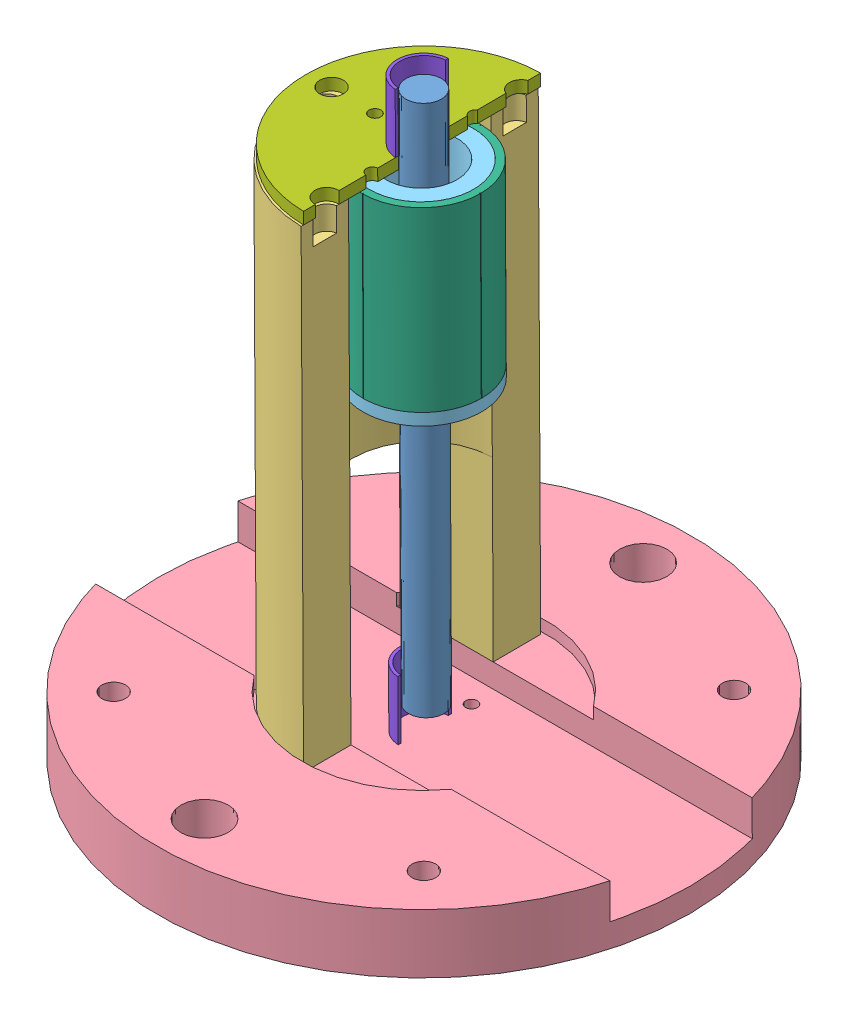
SolidWorks assembly FinalFinal10, configuration Default. Lengths in mm.
Overall size (48.22 72.45 49.76).
10 component instances, 8 part files, 10 mates.
Components (placement in the parent):
- RodCapacitance-1: RodCapacitance [Default] at (-34.9973 26.4173 110.2163) x (-0.024859 -0.005123 0.999678) z (-0.999691 0.000127 -0.024859) size (3 45 3)
- Bearing-7: Bearing [Default] at (-33.9141 58.2749 108.56) x (0 -0.999987 -0.005125) z (-0.999781 0.000107 -0.020933) size (1.6 1.6 1.6)
- Bearing-8: Bearing [Default] at (-37.2061 58.0134 109.9357) x (0 -0.999987 -0.005125) z (-0.999781 0.000107 -0.020933) size (1.6 1.6 1.6)
- 套筒-1: 套筒 [默认] at (-35 26.4344 110.4244) x (-1 0 0) z (0 0.005125 -0.999987) size (20 40 20)
- 底座1-1: 底座1 [默认] at (-35 27.4344 110.4295) x (0 0.005125 -0.999987) z (-1 0 0) size (45 5 45)
- MACOR-2: MACOR [Default] at (-34.9374 53.3058 110.6148) x (1 0 0) z (0 0.005125 -0.999987) size (10 16 10)
- PZTFINAL-1: PZTFINAL [Default] at (-34.9374 51.4338 110.6053) x (1 0 0) z (0 -0.005125 0.999987) size (10 15 10)
- Covercapacitance-4: Covercapacitance [Default] at (-34.9973 67.4349 110.4266) x (0.999662 -0.000133 0.025998) z (0.025998 0.005123 -0.999649) size (20 1 20)
- Ring-1: Ring [Default] at (-34.9973 72.4349 110.4522) x (0 -0.999987 -0.005125) z (0.005125 -0.005125 0.999974) size (5 4.5 4.5)
- Ring-2: Ring [Default] at (-34.9973 29.4354 110.2318) x (0 -0.999987 -0.005125) z (0.684903 0.003734 -0.728625) size (5 4.5 4.5)
Mates (geometry in assembly coordinates):
- Coincident10: coincident aligned: plane of 套筒-1 through (-35 26.4344 110.4244) normal (0 -0.999987 -0.005125); circle of 底座1-1
- Concentric17: concentric anti-aligned: circle of 套筒-1; circle of 底座1-1
- Coincident15: coincident anti-aligned: line of 套筒-1 through (-35.1526 26.4652 104.4245) axis (-1 0 0); line of 底座1-1 through (-43.3104 26.4652 104.4245) axis (1 0 0)
- Lock9: lock: unknown of ?; unknown of ?
- Coincident27: coincident anti-aligned: circle of MACOR-2; circle of PZTFINAL-1
- Coincident31: coincident anti-aligned: circle of 套筒-1; circle of Covercapacitance-4
- Coincident32: coincident aligned: circle of Covercapacitance-4; circle of Ring-1
- Coincident36: coincident anti-aligned: plane of 底座1-1 through (-12.5 24.4037 116.4141) normal (0 0.999987 0.005125); circle of Ring-2
- Concentric18: concentric anti-aligned: circle of RodCapacitance-1; circle of Ring-1
- Concentric19: concentric anti-aligned: circle of RodCapacitance-1; circle of Ring-2
